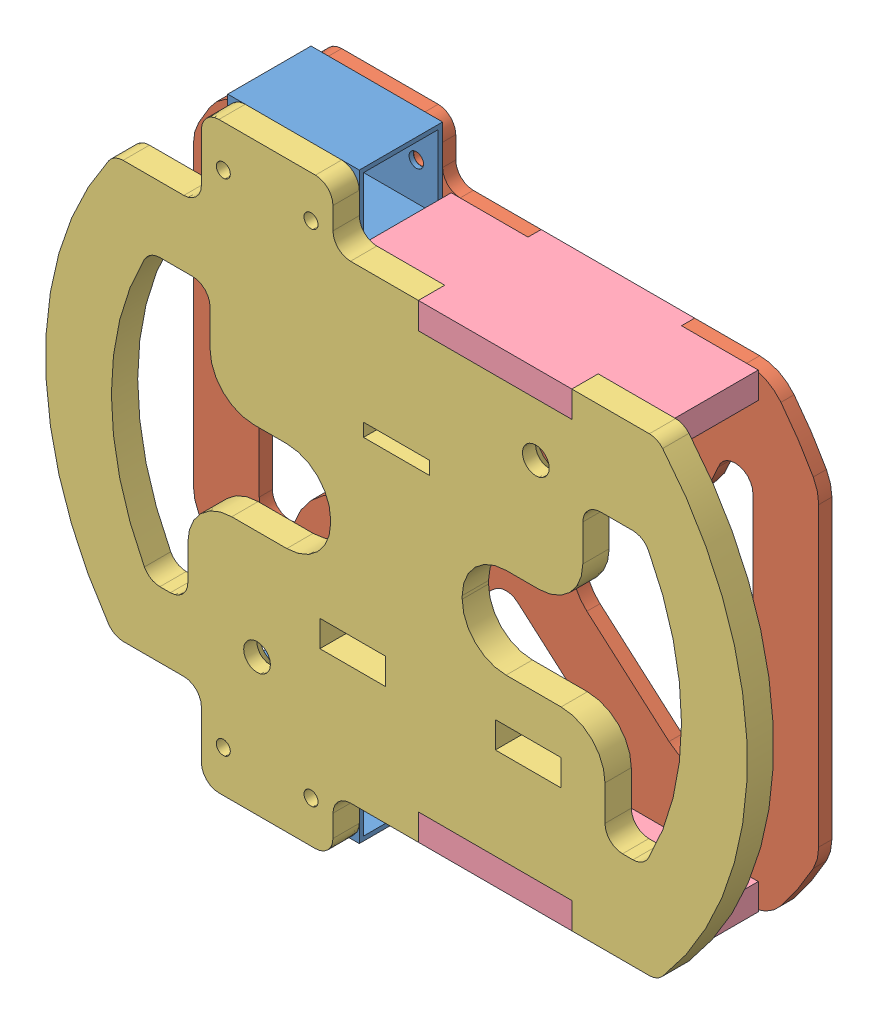
SolidWorks assembly Caixa, configuration Valor predeterminado. Lengths in mm.
Overall size (160 133 28).
6 component instances, 4 part files, 15 mates.
Components (placement in the parent):
- M04.01.01.Tubo caixa-1: M04.01.01.Tubo caixa [Valor predeterminado] at (90.8348 -154.038 -56.5844) x (0 -1 0) z (-1 0 0) size (19 19 30)
- M04.01.02.Inferior1-1: M04.01.02.Inferior1 [Valor predeterminado] at (105.3067 -106.538 -59.5844) x (-1 0 0) z (0 0 1) size (142.58 133 3)
- M04.01.03. Superior-1: M04.01.03. Superior [Valor predeterminado] at (105.3067 -106.538 -37.5844) x (-1 0 0) z (0 0 1) size (160 133 6)
- M04.01.04.Laterais-1: M04.01.04.Laterais [Valor predeterminado] at (127.8103 -154.038 -47.0844) x (1 0 0) z (0 -1 0) size (70 28 6)
- M04.01.01.Tubo caixa-2: M04.01.01.Tubo caixa [Valor predeterminado] at (90.8348 -40.038 -56.5844) x (0 -1 0) z (-1 0 0) size (19 19 30)
- M04.01.04.Laterais-2: M04.01.04.Laterais [Valor predeterminado] at (127.8103 -53.038 -47.0844) x (1 0 0) z (0 -1 0) size (70 28 6)
Mates (geometry in assembly coordinates):
- Concêntrico1: concentric anti-aligned: cylinder of M04.01.01.Tubo caixa-1 through (85.8348 -163.538 -56.5844) axis (0 0 1) radius 1.65; cylinder of M04.01.02.Inferior1-1 through (85.8348 -163.538 -56.5844) axis (0 0 -1) radius 1.6
- Coincidente1: coincident anti-aligned: plane of M04.01.01.Tubo caixa-1 through (60.8348 -154.038 -56.5844) normal (0 0 -1); plane of M04.01.02.Inferior1-1 through (105.3067 -106.538 -56.5844) normal (0 0 1)
- Coincidente2: coincident anti-aligned: plane of M04.01.01.Tubo caixa-1 through (60.8348 -154.038 -37.5844) normal (0 0 1); plane of M04.01.03. Superior-1 through (105.3067 -106.538 -37.5844) normal (0 0 -1)
- Concêntrico2: concentric aligned: cylinder of M04.01.02.Inferior1-1 through (85.8348 -163.538 -56.5844) axis (0 0 -1) radius 1.6; cylinder of M04.01.03. Superior-1 through (85.8348 -163.538 -31.5844) axis (0 0 -1) radius 1.6
- Concêntrico4: concentric aligned: cylinder of M04.01.02.Inferior1-1 through (85.8348 -49.538 -56.5844) axis (0 0 -1) radius 1.6; cylinder of M04.01.03. Superior-1 through (85.8348 -49.538 -31.5844) axis (0 0 -1) radius 1.6
- Concêntrico10: concentric anti-aligned: cylinder of M04.01.01.Tubo caixa-1 through (65.8348 -163.538 -56.5844) axis (0 0 1) radius 1.65; cylinder of M04.01.02.Inferior1-1 through (65.8348 -163.538 -56.5844) axis (0 0 -1) radius 1.6
- Coincidente9: coincident anti-aligned: plane of M04.01.03. Superior-1 through (105.3067 -154.038 -31.5844) normal (0 -1 0); plane of M04.01.04.Laterais-1 through (127.8103 -154.038 -47.0844) normal (0 1 0)
- Coincidente10: coincident anti-aligned: plane of M04.01.03. Superior-1 through (110.3103 -106.538 -31.5844) normal (1 0 0); plane of M04.01.04.Laterais-1 through (110.3103 -160.038 -47.0844) normal (-1 0 0)
- Coincidente11: coincident aligned: plane of M04.01.03. Superior-1 through (105.3067 -106.538 -31.5844) normal (0 0 1); plane of M04.01.04.Laterais-1 through (127.8103 -160.038 -31.5844) normal (0 0 1)
- Concêntrico11: concentric anti-aligned: cylinder of M04.01.02.Inferior1-1 through (65.8348 -49.538 -56.5844) axis (0 0 -1) radius 1.6; cylinder of M04.01.01.Tubo caixa-2 through (65.8348 -49.538 -56.5844) axis (0 0 1) radius 1.65
- Coincidente15: coincident anti-aligned: plane of M04.01.02.Inferior1-1 through (105.3067 -106.538 -56.5844) normal (0 0 1); plane of M04.01.01.Tubo caixa-2 through (60.8348 -40.038 -56.5844) normal (0 0 -1)
- Concêntrico12: concentric anti-aligned: cylinder of M04.01.03. Superior-1 through (85.8348 -49.538 -31.5844) axis (0 0 -1) radius 1.6; cylinder of M04.01.01.Tubo caixa-2 through (85.8348 -49.538 -56.5844) axis (0 0 1) radius 1.65
- Coincidente16: coincident: plane of M04.01.02.Inferior1-1 through (105.3067 -59.038 -56.5844) normal (0 1 0); plane of M04.01.04.Laterais-2 through (113.5865 -59.038 -47.0844) normal (0 -1 0)
- Coincidente17: coincident: plane of M04.01.02.Inferior1-1 through (105.3067 -106.538 -59.5844) normal (0 0 -1); plane of M04.01.04.Laterais-2 through (127.8103 -59.038 -59.5844) normal (0 0 -1)
- Coincidente18: coincident anti-aligned: plane of M04.01.03. Superior-1 through (145.3103 -106.538 -31.5844) normal (-1 0 0); plane of M04.01.04.Laterais-2 through (145.3103 -59.038 -47.0844) normal (1 0 0)
